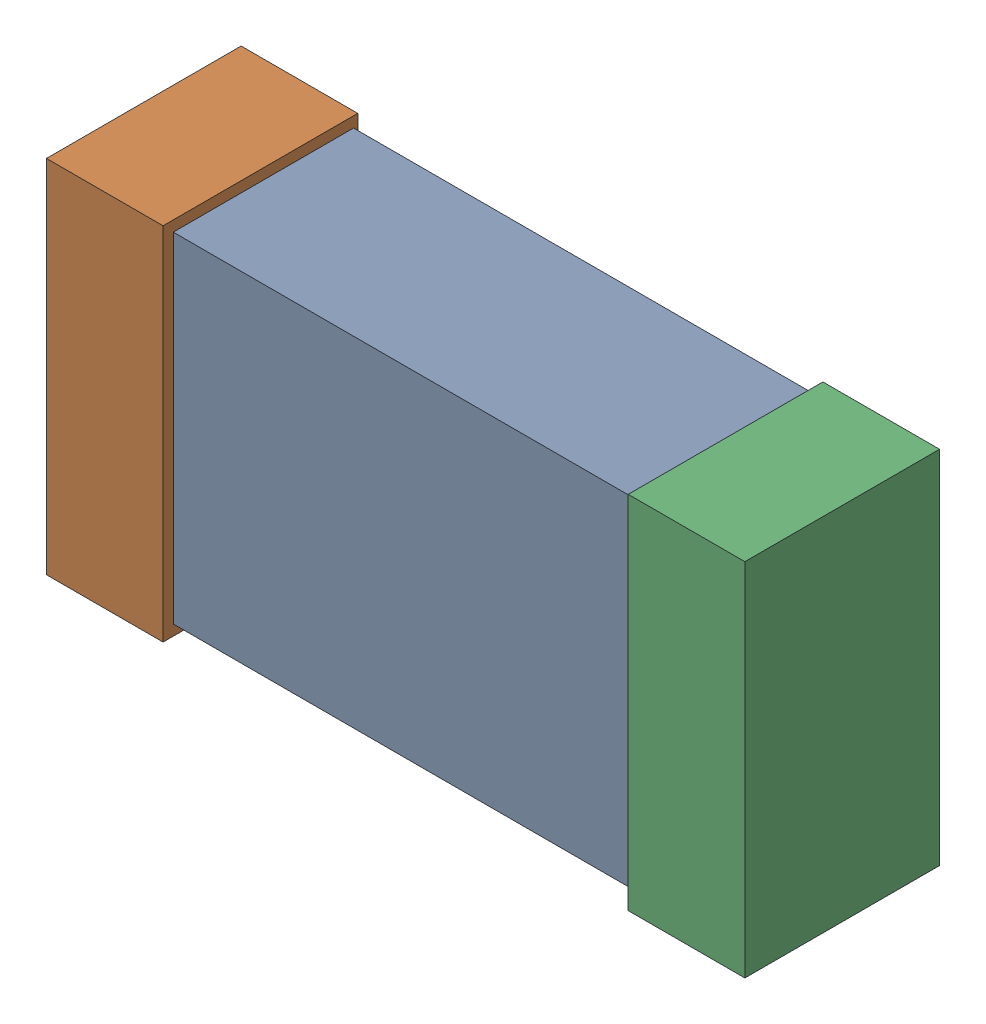
SolidWorks assembly R30, configuration Default. Lengths in mm.
Overall size (1.65 0.85 0.46).
6 component instances, 2 part files, 0 mates.
Components (placement in the parent):
- 432120720_24-1: 432120720_24 [Default] at (22.4266 23.9499 -0.8615) size (1.5 0.8 0.42)
  - Extruded (12)-1: Extruded (12) [Default] at origin size (1.5 0.8 0.42)
- 432120464_50-1: 432120464_50 [Default] at (21.7408 23.9499 -0.8715) size (0.28 0.85 0.46)
  - Extruded (11)-1: Extruded (11) [Default] at origin size (0.28 0.85 0.46)
- 432120464_51-1: 432120464_51 [Default] at (23.1123 23.9499 -0.8715) size (0.28 0.85 0.46)
  - Extruded (11)-1: Extruded (11) [Default] at origin size (0.28 0.85 0.46)
